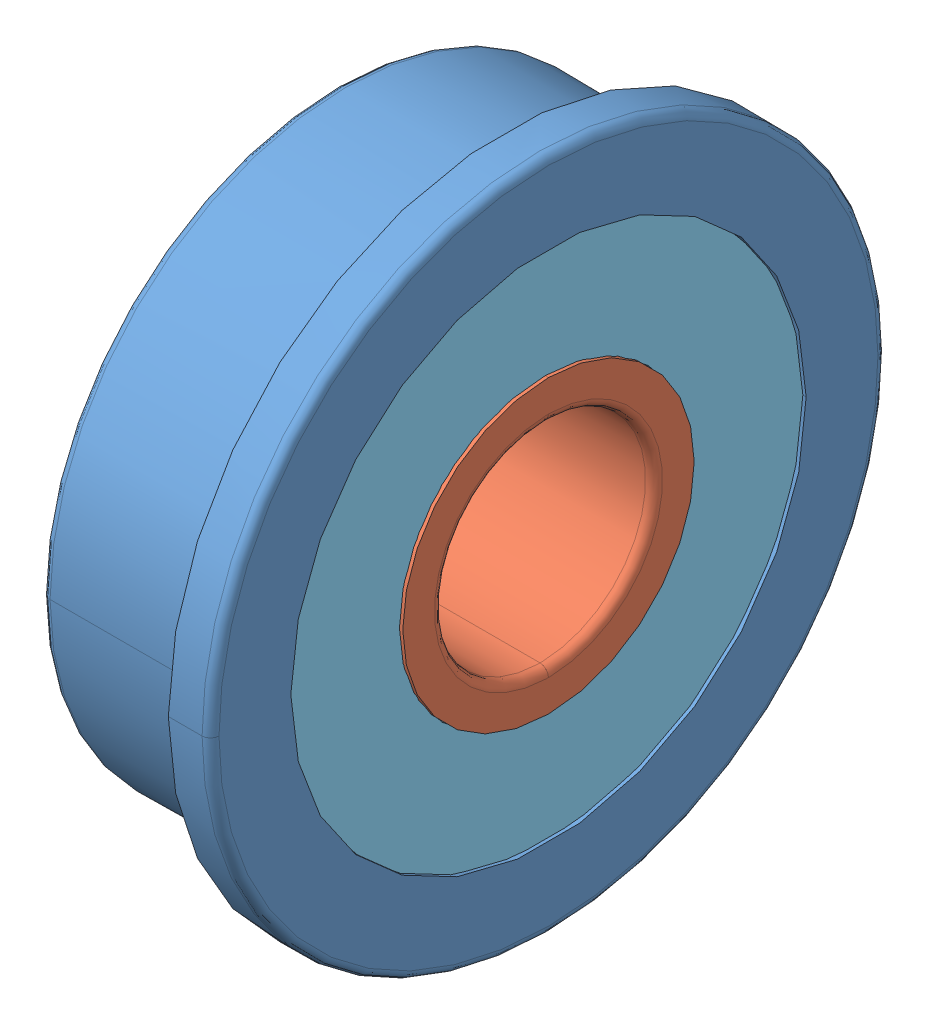
SolidWorks assembly F605ZZ, configuration Default. Lengths in mm.
Overall size (5 16 16).
12 component instances, 5 part files, 0 mates.
Components (placement in the parent):
- _F605ZZ_Outer_Ring_2-1: _F605ZZ_Outer_Ring_2 [Default] at origin size (5 16 16)
- _F605ZZ_Inner_Ring_4-1: _F605ZZ_Inner_Ring_4 [Default] x (1 0 0) z (0 -1 0) size (5 7.79 7.79)
- _F605ZZ_Shield1_6-1: _F605ZZ_Shield1_6 [Default] at (0.625 0 0) x (-1 0 0) z (0 -1 0) size (0.23 12.2 12.2)
- _F605ZZ_Ball_8-1: _F605ZZ_Ball_8 [Default] at (2.5 0 4.75) x (1 0 0) z (0 -1 0) size (2.7 2.7 2.7)
- _F605ZZ_Ball_8-2: _F605ZZ_Ball_8 [Default] at (2.5 -3.3588 3.3588) x (1 0 0) z (0 -1 0) size (2.7 2.7 2.7)
- _F605ZZ_Ball_8-3: _F605ZZ_Ball_8 [Default] at (2.5 -4.75 0) x (1 0 0) z (0 -1 0) size (2.7 2.7 2.7)
- _F605ZZ_Ball_8-4: _F605ZZ_Ball_8 [Default] at (2.5 -3.3588 -3.3588) x (1 0 0) z (0 -1 0) size (2.7 2.7 2.7)
- _F605ZZ_Ball_8-5: _F605ZZ_Ball_8 [Default] at (2.5 0 -4.75) x (1 0 0) z (0 -1 0) size (2.7 2.7 2.7)
- _F605ZZ_Ball_8-6: _F605ZZ_Ball_8 [Default] at (2.5 3.3588 -3.3588) x (1 0 0) z (0 -1 0) size (2.7 2.7 2.7)
- _F605ZZ_Ball_8-7: _F605ZZ_Ball_8 [Default] at (2.5 4.75 0) x (1 0 0) z (0 -1 0) size (2.7 2.7 2.7)
- _F605ZZ_Ball_8-8: _F605ZZ_Ball_8 [Default] at (2.5 3.3588 3.3588) x (1 0 0) z (0 -1 0) size (2.7 2.7 2.7)
- _F605ZZ_Shield2_17-1: _F605ZZ_Shield2_17 [Default] at origin size (0.23 12.2 12.2)
